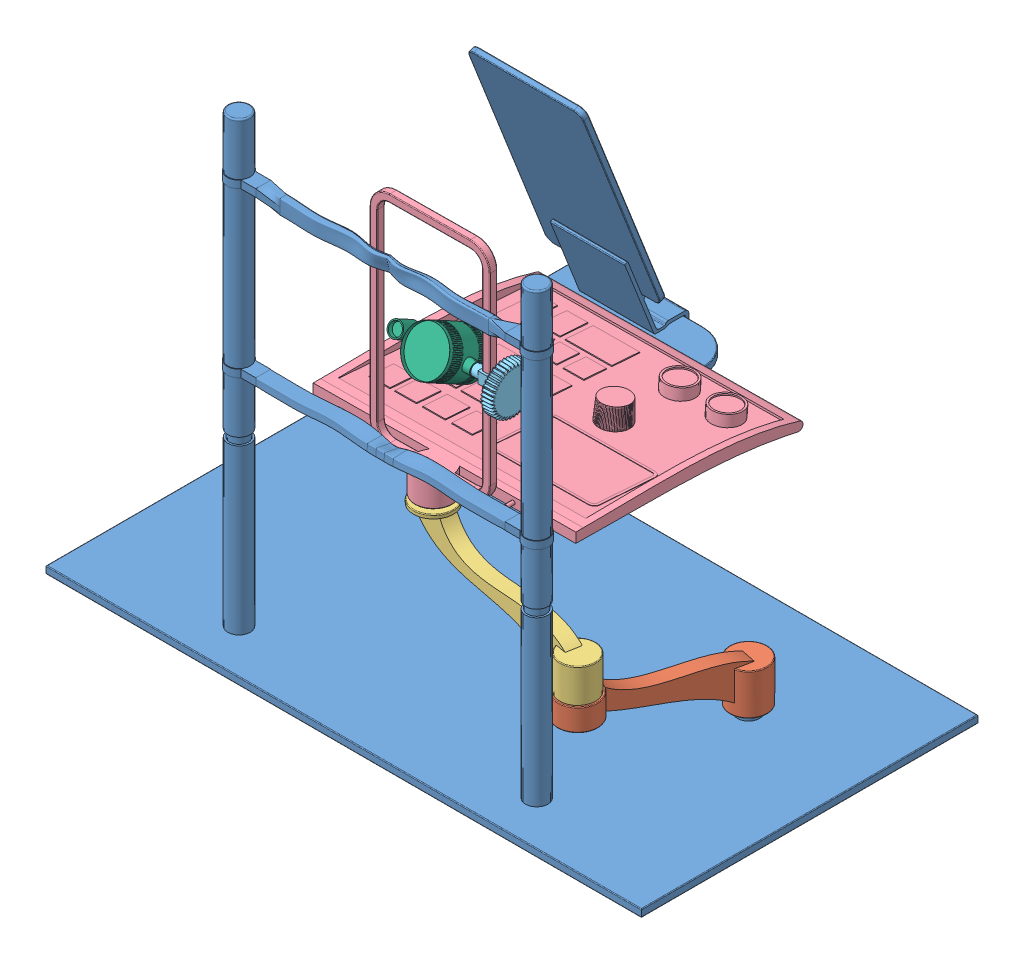
SolidWorks assembly Oralens_assembly, configuration Default. Lengths in mm.
Overall size (400 307.1 361.87).
6 component instances, 6 part files, 10 mates.
Components (placement in the parent):
- Oralens Base-1: Oralens Base [Default] at (16.1934 102.6657 347.7313) size (400 307.1 361.87)
- Oralens Link-1-1: Oralens Link-1 [Default] at (137.4285 112.6757 331.6528) x (-0.980587 0 -0.196085) z (0.196085 0 -0.980587) size (26.93 65.5 123.46)
- Oralens_link-2-1: Oralens_link-2 [Default] at (118.3102 150.6767 427.26) x (-0.984444 0 -0.175697) z (0.175697 0 -0.984444) size (145.31 58.31 26.93)
- Oralens_link-3-1: Oralens_link-3 [Default] at (0.3275 193.1867 406.2033) x (0.999965 0 -0.008342) z (0.008342 0 0.999965) size (175 162.66 173.95)
- Oralens_height adjust-1: Oralens_height adjust [Default] at (37.8247 286.0206 405.89) x (-0.999965 0 0.008342) z (-0.008342 0 -0.999965) size (30.5 32.06 32.06)
- Oralens_cam-1: Oralens_cam [Default] at (8.4219 296.0758 417.6731) x (-0.004001 0.877508 -0.479546) z (-0.00732 -0.479563 -0.877477) size (30 51.34 37.5)
Mates (geometry in assembly coordinates):
- Concentric1: concentric aligned: cylinder of Oralens Base-1 through (137.4285 137.6657 331.6528) axis (0 -1 0) radius 7.5; cylinder of Oralens Link-1-1 through (137.4285 137.6757 331.6528) axis (0 -1 0) radius 7.5005
- Concentric2: concentric aligned: cylinder of Oralens Link-1-1 through (118.3102 178.1757 427.26) axis (0 -1 0) radius 7.5; cylinder of Oralens_link-2-1 through (118.3102 178.1767 427.26) axis (0 -1 0) radius 7.5005
- Concentric3: concentric aligned: cylinder of Oralens_link-2-1 through (0.3275 215.6767 406.2033) axis (0 -1 0) radius 7.5; cylinder of Oralens_link-3-1 through (0.3275 218.1867 406.2033) axis (0 -1 0) radius 7.5
- Distance2: distance = 0.01 mm anti-aligned: plane of Oralens_link-2-1 through (0.3275 215.6767 406.2033) normal (0 1 0); plane of Oralens_link-3-1 through (-26.4992 215.6867 408.9272) normal (0 -1 0)
- Distance3: distance = 0.001 mm anti-aligned: plane of Oralens_link-2-1 through (119.1887 178.1767 422.3378) normal (0 -1 0); plane of Oralens Link-1-1 through (118.3102 178.1757 427.26) normal (0 1 0)
- Distance4: distance = 0.01 mm anti-aligned: plane of Oralens Link-1-1 through (137.4285 137.6757 331.6528) normal (0 -1 0); plane of Oralens Base-1 through (137.4285 137.6657 331.6528) normal (0 1 0)
- Distance5: distance = 0.001 mm anti-aligned: plane of Oralens_height adjust-1 through (35.3034 293.5206 403.4104) normal (0.008342 0 0.999965); plane of Oralens_link-3-1 through (-26.541 352.5352 403.9274) normal (-0.008342 0 -0.999965)
- Distance6: distance = 0.001 mm anti-aligned: plane of Oralens_height adjust-1 through (40.3042 293.5206 403.3687) normal (-0.999965 0 0.008342); plane of Oralens_link-3-1 through (40.3469 352.5352 408.3695) normal (0.999965 0 -0.008342)
- Concentric5: concentric aligned: cylinder of Oralens_height adjust-1 through (23.8252 289.7706 406.0068) axis (0.999965 0 -0.008342) radius 3.25; cylinder of Oralens_cam-1 through (-11.6736 289.7706 406.3029) axis (0.999965 0 -0.008342) radius 3.245
- Distance8: distance = 15.5 mm: cylinder of Oralens_cam-1 through (8.2023 281.6889 391.3488) axis (0.00732 0.479563 0.877477) radius 15; plane of Oralens_height adjust-1 through (23.8252 289.7706 406.0068) normal (-0.999965 0 0.008342)
